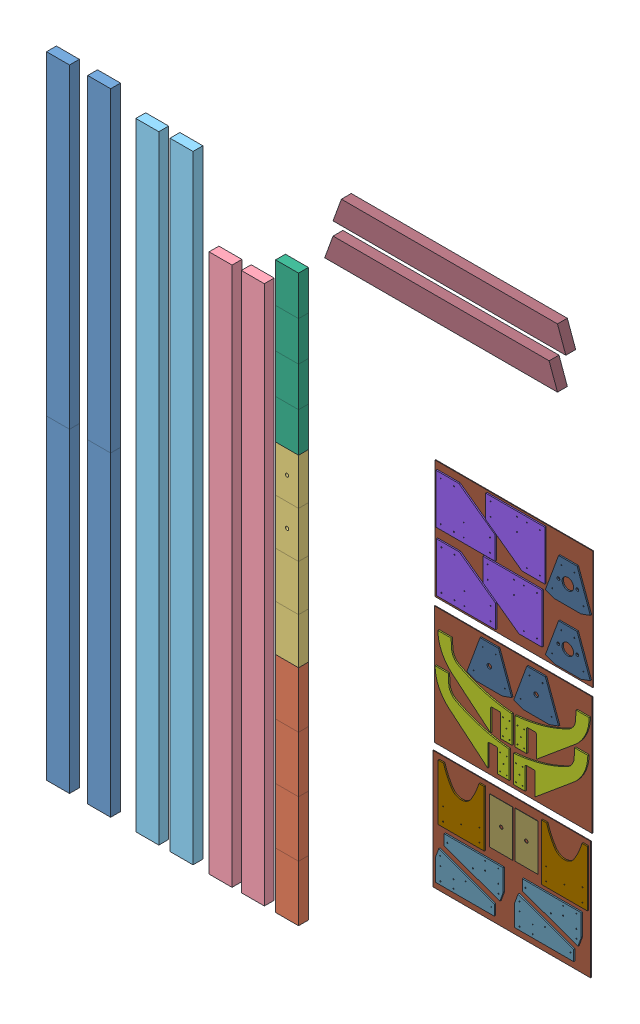
SolidWorks assembly WoodLayout, configuration Default. Lengths in mm.
Overall size (2111.37 2495.64 62.24).
45 component instances, 14 part files, 74 mates.
Components (placement in the parent):
- SimpleLeg-1: SimpleLeg [Default] at (-106.2608 41.2739 1179.6158) size (88.9 1219.2 38.1)
- SimpleLeg-2: SimpleLeg [Default] at (-106.2608 1260.4739 1179.6158) size (88.9 1219.2 38.1)
- SimpleLeg-3: SimpleLeg [Default] at (52.819 41.2739 1179.6158) size (88.9 1219.2 38.1)
- SimpleLeg-4: SimpleLeg [Default] at (52.819 1260.4739 1179.6158) size (88.9 1219.2 38.1)
- CornerBrace-1: CornerBrace [Default] at (823.3817 41.2739 1198.6658) size (88.9 215.9 38.1)
- CornerBrace-2: CornerBrace [Default] at (823.3817 257.1739 1198.6658) size (88.9 215.9 38.1)
- CornerBrace-3: CornerBrace [Default] at (823.3817 473.0739 1198.6658) size (88.9 215.9 38.1)
- CornerBrace-4: CornerBrace [Default] at (823.3817 688.9739 1198.6658) size (88.9 215.9 38.1)
- WidthBeam-1: WidthBeam [Default] at (823.3817 993.7739 1179.6158) x (0 -1 0) z (0 0 1) size (177.8 88.9 38.1)
- WidthBeam-2: WidthBeam [Default] at (823.3817 1171.5739 1179.6158) x (0 -1 0) z (0 0 1) size (177.8 88.9 38.1)
- WidthBeam-3: WidthBeam [End Beam] at (823.3817 1527.1739 1179.6158) x (0 -1 0) z (0 0 1) size (177.8 88.9 38.1)
- WidthBeam-4: WidthBeam [End Beam] at (823.3817 1349.3739 1179.6158) x (0 -1 0) z (0 0 1) size (177.8 88.9 38.1)
- LengthBeam-1: LengthBeam [Default] at (691.138 1082.6739 1179.6158) x (0 0 1) z (0 -1 0) size (38.1 88.9 2082.8)
- LengthBeam-2: LengthBeam [Default] at (566.3218 1082.6739 1179.6158) x (0 0 1) z (0 -1 0) size (38.1 88.9 2082.8)
- FootBeam-1: FootBeam [Long] at (415.4952 1235.0739 1179.6158) x (0 0 1) z (0 -1 0) size (38.1 88.9 2387.6)
- FootBeam-2: FootBeam [Long] at (283.3323 1235.0739 1179.6158) x (0 0 1) z (0 -1 0) size (38.1 88.9 2387.6)
- ShortLengthBrace-1: ShortLengthBrace [Default] at (823.3817 2073.2739 1198.6658) size (88.9 152.4 38.1)
- ShortLengthBrace-2: ShortLengthBrace [Default] at (823.3817 1920.8739 1198.6658) size (88.9 152.4 38.1)
- ShortLengthBrace-3: ShortLengthBrace [Default] at (823.3817 1768.4739 1198.6658) size (88.9 152.4 38.1)
- ShortLengthBrace-4: ShortLengthBrace [Default] at (823.3817 1616.0739 1198.6658) size (88.9 152.4 38.1)
- BackYoke-1: BackYoke [Laser] at (1742.4278 1355.0243 1395.5158) x (-1 0 0) z (0 0 -1) size (286.42 241.31 5.09)
- FootGusset-1: FootGusset [Default] at (1403.3179 1646.041 1217.7158) size (228.6 190.5 5.08)
- FrontYoke-1: FrontYoke [Default] at (1899.8092 946.2153 -567.9042) size (177.8 215.9 5.09)
- SmallGusset-1: SmallGusset [Bushing] at (1609.9084 1348.2851 1217.7158) size (173.52 152.4 5.08)
- SmallGusset-2: SmallGusset [Bushing] at (1790.8982 1343.5215 1217.7158) size (173.52 152.4 5.08)
- FrontYoke-2: FrontYoke [Default] at (1501.5336 947.2855 -567.9042) size (177.8 215.9 5.09)
- SmallGusset-3: SmallGusset [Default] at (1913.2808 1556.4914 1217.7158) size (173.52 152.4 5.08)
- FootGusset-2: FootGusset [Default] at (1813.4789 1639.8095 1217.7158) x (-1 0 0) z (0 0 1) size (228.6 190.5 5.08)
- SmallGusset-4: SmallGusset [Default] at (1913.6525 1775.1765 1217.7158) size (173.52 152.4 5.08)
- FootGusset-3: FootGusset [Default] at (1405.65 1417.6856 1217.7158) size (228.6 190.5 5.08)
- FootGusset-4: FootGusset [Default] at (1824.8385 1856.1723 1217.7158) x (-1 0 0) z (0 0 1) size (228.6 190.5 5.08)
- 18x24_Stock-1: 18x24_Stock [Default] at (1700.309 1635.3374 1215.1758) x (0 0 1) z (-1 0 0) size (2.54 457.2 609.6)
- 18x24_Stock-2: 18x24_Stock [Default] at (1697.7157 1146.0968 1215.1758) x (0 0 1) z (-1 0 0) size (2.54 457.2 609.6)
- BackYoke-3: BackYoke [Laser] at (1665.1686 1355.3959 1044.9958) size (286.42 241.31 5.09)
- BackYoke-4: BackYoke [Laser] at (1731.4163 1231.4805 1395.5158) x (-1 0 0) z (0 0 -1) size (286.42 241.31 5.09)
- BackYoke-5: BackYoke [Laser] at (1659.8447 1226.5688 1044.9958) size (286.42 241.31 5.09)
- 18x24_Stock-3: 18x24_Stock [Default] at (1692.1894 659.7042 1215.1758) x (0 0 1) z (-1 0 0) size (2.54 457.2 609.6)
- ShaftBrace-1: ShaftBrace [Default] at (1749.3503 765.8693 1213.9058) x (0 -1 0) z (0 0 1) size (177.8 88.9 5.08)
- ShaftBrace-2: ShaftBrace [Default] at (1652.401 764.0908 1213.9058) x (0 -1 0) z (0 0 1) size (177.8 88.9 5.08)
- SpreaderBar-1: SpreaderBar [Default] at (1431.8287 2448.0129 1160.5658) size (899.74 88.9 38.1)
- SpreaderBar-2: SpreaderBar [Default] at (1399.6176 2308.4314 1160.5658) size (899.74 88.9 38.1)
- SpreaderBrace-1: SpreaderBrace [Default] at (1965.3705 553.2486 1217.7158) x (0 0 1) z (0 -1 0) size (5.08 227.84 118.73)
- SpreaderBrace-2: SpreaderBrace [Default] at (1708.161 540.8292 1217.7158) x (0 0 1) z (0 1 0) size (5.08 227.84 118.73)
- SpreaderBrace-3: SpreaderBrace [Default] at (1663.7809 553.0963 1217.7158) x (0 0 1) z (0 -1 0) size (5.08 227.84 118.73)
- SpreaderBrace-4: SpreaderBrace [Default] at (1401.7567 539.5724 1217.7158) x (0 0 1) z (0 1 0) size (5.08 227.84 118.73)
Mates (geometry in assembly coordinates):
- Coincident8: coincident aligned: plane of SimpleLeg-1 through (-106.2608 41.2739 1217.7158) normal (0 0 1); plane of SimpleLeg-2 through (-106.2608 1260.4739 1217.7158) normal (0 0 1)
- Coincident9: coincident aligned: line of SimpleLeg-1 through (-17.3608 1260.4739 1217.7158) axis (0 0 -1); line of SimpleLeg-2 through (-17.3608 1260.4739 1217.7158) axis (0 0 -1)
- Coincident10: coincident anti-aligned: line of SimpleLeg-3 through (141.719 1260.4739 1217.7158) axis (-1 0 0); line of SimpleLeg-4 through (52.819 1260.4739 1217.7158) axis (1 0 0)
- Coincident11: coincident aligned: line of SimpleLeg-3 through (141.719 1260.4739 1217.7158) axis (0 0 -1); line of SimpleLeg-4 through (141.719 1260.4739 1217.7158) axis (0 0 -1)
- Coincident12: coincident anti-aligned: line of SimpleLeg-1 through (-17.3608 1260.4739 1217.7158) axis (-1 0 0); line of SimpleLeg-2 through (-106.2608 1260.4739 1217.7158) axis (1 0 0)
- Coincident13: coincident aligned: line of SimpleLeg-1 through (-106.2608 41.2739 1217.7158) axis (1 0 0); line of SimpleLeg-3 through (52.819 41.2739 1217.7158) axis (1 0 0)
- Coincident14: coincident aligned: plane of SimpleLeg-1 through (-106.2608 41.2739 1217.7158) normal (0 0 1); plane of SimpleLeg-3 through (52.819 41.2739 1217.7158) normal (0 0 1)
- Coincident15: coincident aligned: line of SimpleLeg-3 through (52.819 41.2739 1217.7158) axis (1 0 0); line of FootBeam-2 through (238.8823 41.2739 1217.7158) axis (1 0 0)
- Coincident16: coincident aligned: plane of SimpleLeg-3 through (52.819 41.2739 1217.7158) normal (0 0 1); plane of FootBeam-2 through (283.3323 1235.0739 1217.7158) normal (0 0 1)
- Coincident17: coincident aligned: line of FootBeam-1 through (371.0452 41.2739 1217.7158) axis (1 0 0); line of FootBeam-2 through (238.8823 41.2739 1217.7158) axis (1 0 0)
- Coincident18: coincident aligned: plane of FootBeam-1 through (415.4952 1235.0739 1217.7158) normal (0 0 1); plane of FootBeam-2 through (283.3323 1235.0739 1217.7158) normal (0 0 1)
- Coincident19: coincident aligned: line of LengthBeam-2 through (521.8718 41.2739 1217.7158) axis (1 0 0); line of FootBeam-1 through (371.0452 41.2739 1217.7158) axis (1 0 0)
- Coincident20: coincident aligned: plane of LengthBeam-2 through (566.3218 1082.6739 1217.7158) normal (0 0 1); plane of FootBeam-1 through (415.4952 1235.0739 1217.7158) normal (0 0 1)
- Coincident21: coincident aligned: line of LengthBeam-1 through (646.688 41.2739 1217.7158) axis (1 0 0); line of LengthBeam-2 through (521.8718 41.2739 1217.7158) axis (1 0 0)
- Coincident22: coincident aligned: plane of LengthBeam-1 through (691.138 1082.6739 1217.7158) normal (0 0 1); plane of LengthBeam-2 through (566.3218 1082.6739 1217.7158) normal (0 0 1)
- Coincident23: coincident aligned: line of CornerBrace-3 through (778.9317 688.9739 1217.7158) axis (1 0 0); line of CornerBrace-4 through (778.9317 688.9739 1217.7158) axis (1 0 0)
- Coincident24: coincident aligned: line of CornerBrace-3 through (867.8317 688.9739 1217.7158) axis (0 0 -1); line of CornerBrace-4 through (867.8317 688.9739 1217.7158) axis (0 0 -1)
- Coincident25: coincident aligned: line of CornerBrace-2 through (867.8317 473.0739 1217.7158) axis (0 0 -1); line of CornerBrace-3 through (867.8317 473.0739 1217.7158) axis (0 0 -1)
- Coincident26: coincident aligned: line of CornerBrace-2 through (778.9317 473.0739 1217.7158) axis (1 0 0); line of CornerBrace-3 through (778.9317 473.0739 1217.7158) axis (1 0 0)
- Coincident27: coincident aligned: line of CornerBrace-1 through (867.8317 257.1739 1217.7158) axis (0 0 -1); line of CornerBrace-2 through (867.8317 257.1739 1217.7158) axis (0 0 -1)
- Coincident28: coincident aligned: line of CornerBrace-1 through (778.9317 257.1739 1217.7158) axis (1 0 0); line of CornerBrace-2 through (778.9317 257.1739 1217.7158) axis (1 0 0)
- Coincident29: coincident aligned: line of CornerBrace-4 through (778.9317 904.8739 1217.7158) axis (1 0 0); line of WidthBeam-1 through (778.9317 904.8739 1217.7158) axis (1 0 0)
- Coincident30: coincident aligned: line of CornerBrace-4 through (867.8317 904.8739 1217.7158) axis (0 0 -1); line of WidthBeam-1 through (867.8317 904.8739 1217.7158) axis (0 0 -1)
- Coincident31: coincident anti-aligned: line of WidthBeam-1 through (867.8317 1082.6739 1217.7158) axis (-1 0 0); line of WidthBeam-2 through (778.9317 1082.6739 1217.7158) axis (1 0 0)
- Coincident32: coincident aligned: line of WidthBeam-1 through (867.8317 1082.6739 1217.7158) axis (0 0 -1); line of WidthBeam-2 through (867.8317 1082.6739 1217.7158) axis (0 0 -1)
- Coincident33: coincident aligned: line of WidthBeam-2 through (867.8317 1260.4739 1217.7158) axis (0 0 -1); line of WidthBeam-4 through (867.8317 1260.4739 1217.7158) axis (0 0 -1)
- Coincident34: coincident anti-aligned: line of WidthBeam-2 through (867.8317 1260.4739 1179.6158) axis (-1 0 0); line of WidthBeam-4 through (778.9317 1260.4739 1179.6158) axis (1 0 0)
- Coincident35: coincident anti-aligned: line of WidthBeam-3 through (778.9317 1438.2739 1217.7158) axis (1 0 0); line of WidthBeam-4 through (867.8317 1438.2739 1217.7158) axis (-1 0 0)
- Coincident36: coincident aligned: line of WidthBeam-3 through (867.8317 1438.2739 1217.7158) axis (0 0 -1); line of WidthBeam-4 through (867.8317 1438.2739 1217.7158) axis (0 0 -1)
- Coincident37: coincident aligned: line of ShortLengthBrace-3 through (778.9317 1768.4739 1217.7158) axis (1 0 0); line of ShortLengthBrace-4 through (778.9317 1768.4739 1217.7158) axis (1 0 0)
- Coincident38: coincident aligned: line of ShortLengthBrace-3 through (867.8317 1768.4739 1217.7158) axis (0 0 -1); line of ShortLengthBrace-4 through (867.8317 1768.4739 1217.7158) axis (0 0 -1)
- Coincident39: coincident aligned: line of ShortLengthBrace-2 through (778.9317 1920.8739 1217.7158) axis (1 0 0); line of ShortLengthBrace-3 through (778.9317 1920.8739 1217.7158) axis (1 0 0)
- Coincident40: coincident aligned: line of ShortLengthBrace-2 through (867.8317 1920.8739 1217.7158) axis (0 0 -1); line of ShortLengthBrace-3 through (867.8317 1920.8739 1217.7158) axis (0 0 -1)
- Coincident41: coincident aligned: line of ShortLengthBrace-1 through (867.8317 2073.2739 1217.7158) axis (0 0 -1); line of ShortLengthBrace-2 through (867.8317 2073.2739 1217.7158) axis (0 0 -1)
- Coincident42: coincident aligned: line of ShortLengthBrace-1 through (778.9317 2073.2739 1217.7158) axis (1 0 0); line of ShortLengthBrace-2 through (778.9317 2073.2739 1217.7158) axis (1 0 0)
- Coincident43: coincident anti-aligned: line of WidthBeam-3 through (867.8317 1616.0739 1217.7158) axis (-1 0 0); line of ShortLengthBrace-4 through (778.9317 1616.0739 1217.7158) axis (1 0 0)
- Coincident45: coincident aligned: line of WidthBeam-3 through (867.8317 1616.0739 1217.7158) axis (0 0 -1); line of ShortLengthBrace-4 through (867.8317 1616.0739 1217.7158) axis (0 0 -1)
- Coincident47: coincident aligned: line of CornerBrace-1 through (778.9317 41.2739 1217.7158) axis (1 0 0); line of LengthBeam-1 through (646.688 41.2739 1217.7158) axis (1 0 0)
- Coincident48: coincident aligned: plane of CornerBrace-1 through (778.9317 257.1739 1217.7158) normal (0 0 1); plane of LengthBeam-1 through (691.138 1082.6739 1217.7158) normal (0 0 1)
- Coincident49: coincident aligned: plane of SimpleLeg-1 through (-106.2608 41.2739 1217.7158) normal (0 0 1); plane of 18x24_Stock-1 through (1700.309 1635.3374 1217.7158) normal (0 0 1)
- Parallel1: parallel aligned: line of SimpleLeg-1 through (-106.2608 1260.4739 1217.7158) axis (0 -1 0); line of 18x24_Stock-1 through (1395.509 1863.9374 1217.7158) axis (0 -1 0)
- Parallel2: parallel aligned: line of FootGusset-4 through (1824.8385 1856.1723 1222.7958) axis (-1 0 0); line of 18x24_Stock-1 through (2005.109 1863.9374 1217.7158) axis (-1 0 0)
- Parallel3: parallel anti-aligned: plane of FootGusset-4 through (1824.8385 1856.1723 1217.7158) normal (0 0 -1); plane of 18x24_Stock-1 through (1700.309 1635.3374 1217.7158) normal (0 0 1)
- Parallel4: parallel anti-aligned: line of FootGusset-2 through (1813.4789 1639.8095 1222.7958) axis (-1 0 0); line of 18x24_Stock-1 through (1395.509 1406.7374 1217.7158) axis (1 0 0)
- Coincident54: coincident anti-aligned: plane of FootGusset-2 through (1813.4789 1639.8095 1217.7158) normal (0 0 -1); plane of 18x24_Stock-1 through (1700.309 1635.3374 1217.7158) normal (0 0 1)
- Perpendicular1: perpendicular: line of 18x24_Stock-2 through (1392.9157 917.4968 1217.7158) axis (1 0 0); line of BackYoke-5 through (1704.2947 1039.7806 1222.7958) axis (0 -1 0)
- Coincident56: coincident anti-aligned: plane of 18x24_Stock-2 through (1697.7157 1146.0968 1217.7158) normal (0 0 1); plane of BackYoke-5 through (1659.8447 1226.5688 1217.7158) normal (0 0 -1)
- Coincident57: coincident anti-aligned: plane of 18x24_Stock-2 through (1697.7157 1146.0968 1217.7158) normal (0 0 1); plane of BackYoke-4 through (1731.4163 1231.4805 1217.7158) normal (0 0 -1)
- Parallel6: parallel aligned: line of 18x24_Stock-2 through (1392.9157 917.4968 1217.7158) axis (1 0 0); line of BackYoke-4 through (1642.5163 939.3805 1222.7958) axis (1 0 0)
- Coincident59: coincident anti-aligned: plane of BackYoke-1 through (1742.4278 1355.0243 1217.7158) normal (0 0 -1); plane of 18x24_Stock-2 through (1697.7157 1146.0968 1217.7158) normal (0 0 1)
- Parallel7: parallel aligned: line of BackYoke-1 through (1653.5278 1062.9243 1222.7958) axis (1 0 0); line of 18x24_Stock-2 through (1392.9157 917.4968 1217.7158) axis (1 0 0)
- Coincident61: coincident aligned: plane of 18x24_Stock-2 through (1697.7157 1146.0968 1217.7158) normal (0 0 1); plane of 18x24_Stock-3 through (1692.1894 659.7042 1217.7158) normal (0 0 1)
- Parallel8: parallel: line of 18x24_Stock-2 through (1392.9157 917.4968 1217.7158) axis (1 0 0); line of 18x24_Stock-3 through (1996.9894 888.3042 1217.7158) axis (-1 0 0)
- Coincident63: coincident aligned: plane of 18x24_Stock-1 through (1700.309 1635.3374 1217.7158) normal (0 0 1); plane of 18x24_Stock-2 through (1697.7157 1146.0968 1217.7158) normal (0 0 1)
- Coincident64: coincident anti-aligned: plane of FootGusset-1 through (1403.3179 1646.041 1217.7158) normal (0 0 -1); plane of 18x24_Stock-1 through (1700.309 1635.3374 1217.7158) normal (0 0 1)
- Coincident65: coincident anti-aligned: plane of SmallGusset-1 through (1609.9084 1348.2851 1217.7158) normal (0 0 -1); plane of 18x24_Stock-1 through (1700.309 1635.3374 1217.7158) normal (0 0 1)
- Coincident66: coincident anti-aligned: plane of FootGusset-4 through (1824.8385 1856.1723 1217.7158) normal (0 0 -1); plane of 18x24_Stock-1 through (1700.309 1635.3374 1217.7158) normal (0 0 1)
- Coincident67: coincident anti-aligned: plane of SmallGusset-3 through (1913.2808 1556.4914 1217.7158) normal (0 0 -1); plane of 18x24_Stock-1 through (1700.309 1635.3374 1217.7158) normal (0 0 1)
- Coincident68: coincident anti-aligned: plane of FootGusset-3 through (1405.65 1417.6856 1217.7158) normal (0 0 -1); plane of 18x24_Stock-1 through (1700.309 1635.3374 1217.7158) normal (0 0 1)
- Coincident69: coincident anti-aligned: plane of 18x24_Stock-2 through (1697.7157 1146.0968 1217.7158) normal (0 0 1); plane of BackYoke-3 through (1665.1686 1355.3959 1217.7158) normal (0 0 -1)
- Coincident70: coincident anti-aligned: plane of SmallGusset-2 through (1790.8982 1343.5215 1217.7158) normal (0 0 -1); plane of 18x24_Stock-2 through (1697.7157 1146.0968 1217.7158) normal (0 0 1)
- Coincident71: coincident anti-aligned: plane of SmallGusset-4 through (1913.6525 1775.1765 1217.7158) normal (0 0 -1); plane of 18x24_Stock-2 through (1697.7157 1146.0968 1217.7158) normal (0 0 1)
- Coincident72: coincident anti-aligned: plane of FrontYoke-2 through (1546.8422 816.1512 1217.7158) normal (0 0 -1); plane of 18x24_Stock-3 through (1692.1894 659.7042 1217.7158) normal (0 0 1)
- Coincident73: coincident anti-aligned: plane of FrontYoke-1 through (1945.1178 815.081 1217.7158) normal (0 0 -1); plane of 18x24_Stock-3 through (1692.1894 659.7042 1217.7158) normal (0 0 1)
- Parallel9: parallel anti-aligned: line of 18x24_Stock-3 through (1996.9894 888.3042 1217.7158) axis (-1 0 0); line of ShaftBrace-2 through (1607.951 675.1908 1218.9858) axis (1 0 0)
- Parallel10: parallel anti-aligned: line of 18x24_Stock-3 through (1996.9894 888.3042 1217.7158) axis (-1 0 0); line of ShaftBrace-1 through (1704.9003 676.9693 1218.9858) axis (1 0 0)
- Coincident74: coincident anti-aligned: plane of 18x24_Stock-3 through (1692.1894 659.7042 1217.7158) normal (0 0 1); plane of SpreaderBrace-1 through (1965.3705 553.2486 1217.7158) normal (0 0 -1)
- Coincident75: coincident anti-aligned: plane of 18x24_Stock-3 through (1692.1894 659.7042 1217.7158) normal (0 0 1); plane of SpreaderBrace-2 through (1708.161 540.8292 1217.7158) normal (0 0 -1)
- Coincident76: coincident anti-aligned: plane of 18x24_Stock-3 through (1692.1894 659.7042 1217.7158) normal (0 0 1); plane of SpreaderBrace-3 through (1663.7809 553.0963 1217.7158) normal (0 0 -1)
- Coincident77: coincident anti-aligned: plane of 18x24_Stock-3 through (1692.1894 659.7042 1217.7158) normal (0 0 1); plane of SpreaderBrace-4 through (1401.7567 539.5724 1217.7158) normal (0 0 -1)
- Parallel11: parallel anti-aligned: line of 18x24_Stock-3 through (1387.3894 431.1042 1217.7158) axis (1 0 0); line of SpreaderBrace-1 through (1965.3705 636.1773 1222.7958) axis (-1 0 0)
- Parallel12: parallel aligned: line of 18x24_Stock-3 through (1387.3894 431.1042 1217.7158) axis (1 0 0); line of SpreaderBrace-2 through (1708.161 457.9005 1222.7958) axis (1 0 0)
- Parallel13: parallel anti-aligned: line of 18x24_Stock-3 through (1387.3894 431.1042 1217.7158) axis (1 0 0); line of SpreaderBrace-3 through (1663.7809 636.025 1222.7958) axis (-1 0 0)
- Parallel14: parallel aligned: line of 18x24_Stock-3 through (1387.3894 431.1042 1217.7158) axis (1 0 0); line of SpreaderBrace-4 through (1401.7567 456.6437 1222.7958) axis (1 0 0)
